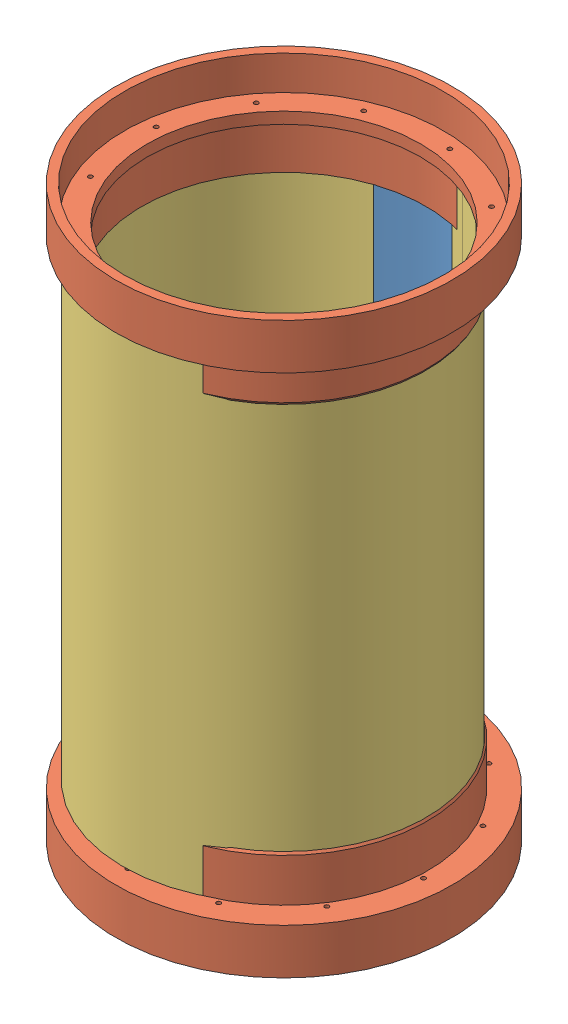
SolidWorks assembly Aluminum Bridge Assembly Example, configuration Default. Lengths in mm.
Overall size (129.74 158.75 129.74).
4 component instances, 3 part files, 9 mates.
Components (placement in the parent):
- Al bridge-1: Al bridge [Default] at (9.6443 -1.3085 166.2401) size (26.08 133.35 3.76)
- Main Ring-1: Main Ring [Default] at (9.6443 135.2165 166.2401) x (0.991704 0 0.128541) z (-0.128541 0 0.991704) size (93.73 25.4 93.73)
- Main Ring-2: Main Ring [Default] at (9.6443 -4.4835 166.2401) x (0.836816 0 0.547485) z (0.547485 0 -0.836816) size (93.73 25.4 93.73)
- PTFE wrapped sheet-1: PTFE wrapped sheet [Default] at (6.238 -1.3085 165.9149) x (0.996692 0 0.081275) z (-0.081275 0 0.996692) size (83.44 133.35 83.38)
Mates (geometry in assembly coordinates):
- Concentric1: concentric anti-aligned: cylinder of Al bridge-1 through (9.6443 132.0415 166.2401) axis (0 -1 0) radius 40.132; cylinder of Main Ring-1 through (9.6443 190.2165 166.2401) axis (0 1 0) radius 40.005
- Coincident1: coincident anti-aligned: plane of Al bridge-1 through (9.6443 132.0415 166.2401) normal (0 1 0); plane of Main Ring-1 through (-30.0289 132.0415 161.0978) normal (0 -1 0)
- Concentric2: concentric aligned: cylinder of Al bridge-1 through (9.6443 132.0415 166.2401) axis (0 -1 0) radius 40.132; cylinder of Main Ring-2 through (9.6443 -59.4835 166.2401) axis (0 -1 0) radius 40.005
- Coincident2: coincident anti-aligned: plane of Al bridge-1 through (9.6443 -1.3085 166.2401) normal (0 -1 0); plane of Main Ring-2 through (-23.8326 -1.3085 144.338) normal (0 1 0)
- Coincident6: coincident aligned: line of Al bridge-1 through (11.9021 132.0415 124.5817) axis (0 -1 0); line of PTFE wrapped sheet-1 through (11.9021 132.0415 124.5817) axis (0 -1 0)
- Parallel3: parallel aligned: line of Al bridge-1 through (7.3886 132.0415 124.5816) axis (0 -1 0); line of PTFE wrapped sheet-1 through (7.3452 132.0415 124.2101) axis (0 -1 0)
- Parallel4: parallel aligned: line of Al bridge-1 through (22.6828 132.0415 128.2852) axis (0 -1 0); line of PTFE wrapped sheet-1 through (22.3038 132.0415 129.139) axis (0 -1 0)
- Parallel5: parallel aligned: line of Al bridge-1 through (-3.3923 132.0415 128.2845) axis (0 -1 0); line of PTFE wrapped sheet-1 through (-3.6989 132.0415 127.0326) axis (0 -1 0)
- Coincident11: coincident anti-aligned: plane of Main Ring-2 through (-23.8326 -1.3085 144.338) normal (0 1 0); plane of PTFE wrapped sheet-1 through (6.238 -1.3085 165.9149) normal (0 -1 0)
